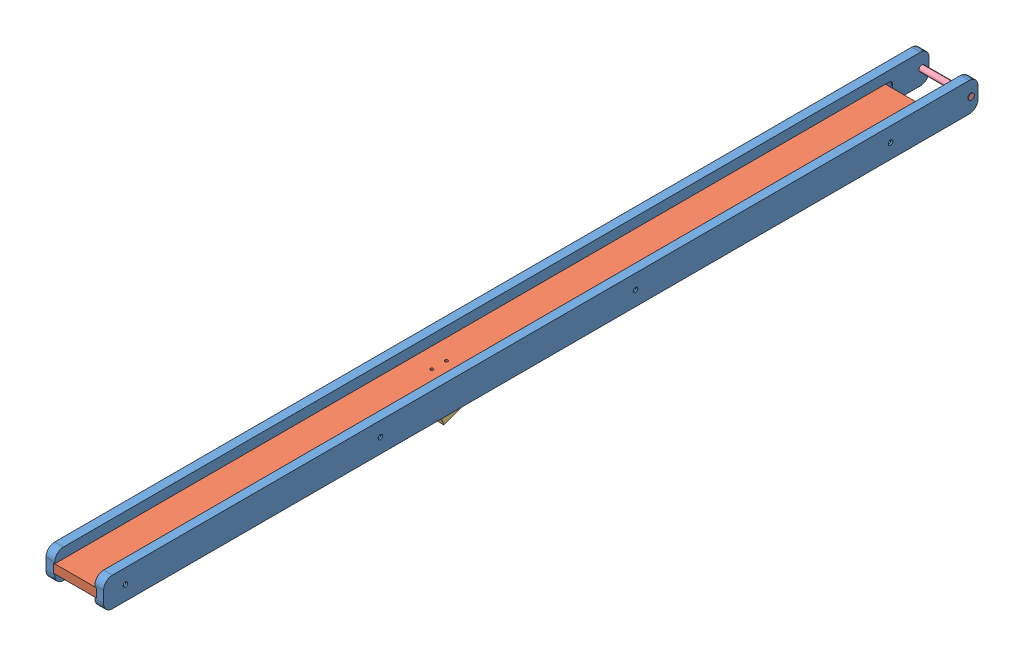
SolidWorks assembly TripodLeg, configuration Default. Lengths in mm.
Overall size (85 82.38 1200).
5 component instances, 4 part files, 11 mates.
Components (placement in the parent):
- TripodLegSide-1: TripodLegSide [Default] at (-172.7239 393.2904 1248.5732) size (12 40 1200)
- TripodLegSide-2: TripodLegSide [Default] at (-105.7239 393.2904 1248.5732) x (-1 0 0) z (0 0 1) size (12 40 1200)
- TripodLegBase-1: TripodLegBase [Default] at (-139.2239 393.2904 1278.5732) size (59 12 1140)
- TripodSpreaderSupport-1: TripodSpreaderSupport [Default] at (-139.2239 330.9088 1348.1079) x (0 0.939693 0.34202) z (-1 0 0) size (60 40 12)
- slotted cheese head screw_din-1: slotted cheese head screw_din [ISO 1207 - M8 x 80 --- 38N] at (-183.7239 393.2904 658.5732) size (85 13 13)
Mates (geometry in assembly coordinates):
- Coincident1: coincident anti-aligned: plane of TripodLegSide-2 through (-109.7239 393.2904 1248.5732) normal (-1 0 0); plane of TripodLegBase-1 through (-109.7239 399.2904 1848.5732) normal (1 0 0)
- Coincident2: coincident anti-aligned: plane of TripodLegSide-2 through (-109.7239 387.2904 698.5732) normal (0 1 0); plane of TripodLegBase-1 through (-168.7239 387.2904 1848.5732) normal (0 -1 0)
- Coincident3: coincident aligned: plane of TripodLegSide-2 through (-105.7239 393.2904 1848.5732) normal (0 0 1); plane of TripodLegBase-1 through (-139.2239 393.2904 1848.5732) normal (0 0 1)
- Coincident4: coincident anti-aligned: plane of TripodLegSide-1 through (-168.7239 393.2904 1248.5732) normal (1 0 0); plane of TripodLegBase-1 through (-168.7239 399.2904 1848.5732) normal (-1 0 0)
- Coincident5: coincident anti-aligned: plane of TripodLegSide-1 through (-168.7239 399.2904 698.5732) normal (0 -1 0); plane of TripodLegBase-1 through (-168.7239 399.2904 1848.5732) normal (0 1 0)
- Coincident6: coincident aligned: plane of TripodLegSide-1 through (-172.7239 393.2904 1848.5732) normal (0 0 1); plane of TripodLegBase-1 through (-139.2239 393.2904 1848.5732) normal (0 0 1)
- Coincident7: coincident anti-aligned: plane of TripodLegBase-1 through (-168.7239 387.2904 1848.5732) normal (0 -1 0); plane of TripodSpreaderSupport-1 through (-145.2239 387.2904 1326.062) normal (0 1 0)
- Coincident8: coincident anti-aligned: plane of TripodLegBase-1 through (-139.2239 393.2904 1278.5732) normal (1 0 0); plane of TripodSpreaderSupport-1 through (-139.2239 330.9088 1348.1079) normal (-1 0 0)
- Distance1: distance = 451 mm: plane of TripodSpreaderSupport-1 through (-145.2239 387.2904 1368.6291) normal (0 -0.34202 0.939693); line of TripodLegBase-1 through (-167.7239 387.2904 1848.5732) axis (1 0 0)
- Concentric1: concentric anti-aligned: cylinder of TripodLegSide-1 through (-178.7249 393.2904 658.5732) axis (1 0 0) radius 4; cylinder of slotted cheese head screw_din-1 through (-209.1239 393.2904 658.5732) axis (-1 0 0) radius 4
- Coincident11: coincident anti-aligned: plane of TripodLegSide-1 through (-178.7239 413.2904 1848.5732) normal (-1 0 0); plane of slotted cheese head screw_din-1 through (-178.7239 397.2904 658.5732) normal (1 0 0)
